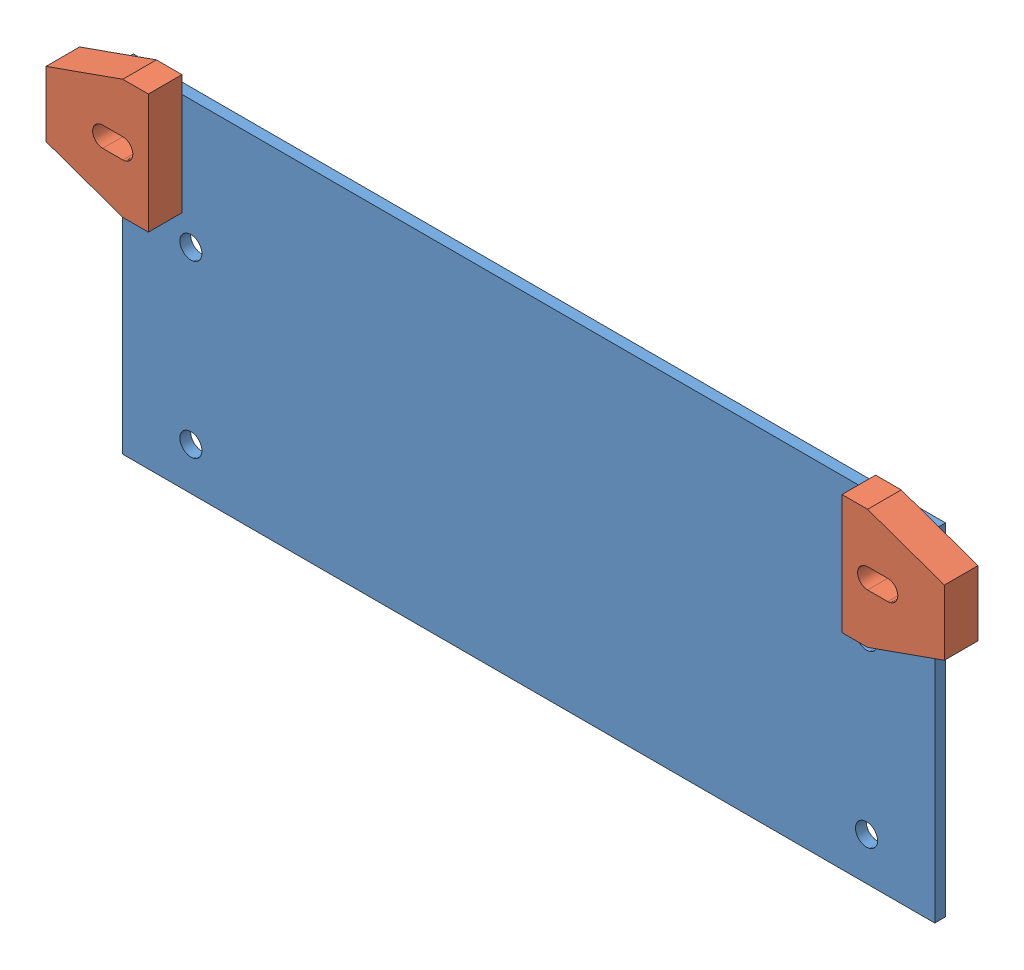
SolidWorks assembly pcbassy, configuration Default. Lengths in mm.
Overall size (133.75 53.35 6.6).
3 component instances, 2 part files, 6 mates.
Components (placement in the parent):
- pcb-1: pcb [Default] at origin size (120.9 50.8 1.6)
- sensor-2: sensor [Default] at (51.6469 25.4 6.6038) x (0 1 0) z (-1 0 0) size (17.81 5 15.24)
- sensor-3: sensor [Default] at (-51.6185 25.4 6.6038) x (0 -1 0) z (1 0 0) size (17.81 5 15.24)
Mates (geometry in assembly coordinates):
- Slot1: slot anti-aligned: plane of sensor-3 through (-55.4285 23.9014 1.6) normal (0 1 0); cylinder of pcb-1 through (-56.896 25.4 1.6) axis (0 0 -1) radius 1.4986; cylinder of sensor-3 through (-55.4285 25.4 1.6) axis (0 0 1) radius 1.4986
- Slot2: slot anti-aligned: plane of sensor-2 through (55.4569 23.9014 1.6) normal (0 1 0); cylinder of pcb-1 through (56.896 25.4 1.6) axis (0 0 -1) radius 1.4986; cylinder of sensor-2 through (58.4541 25.4 1.6) axis (0 0 1) radius 1.4986
- Coincident1: coincident anti-aligned: plane of pcb-1 through (0 0 1.6) normal (0 0 1); plane of sensor-2 through (51.6469 25.4 1.6) normal (0 0 -1)
- Coincident2: coincident anti-aligned: plane of pcb-1 through (0 0 1.6) normal (0 0 1); plane of sensor-3 through (-51.6185 25.4 1.6) normal (0 0 -1)
- Parallel1: parallel aligned: plane of pcb-1 through (-60.452 -19.05 1.6) normal (-1 0 0); plane of sensor-3 through (-66.8585 30.2514 1.6) normal (-1 0 0)
- Parallel2: parallel aligned: plane of pcb-1 through (60.452 19.05 1.6) normal (1 0 0); plane of sensor-2 through (66.8869 20.5486 1.6) normal (1 0 0)
